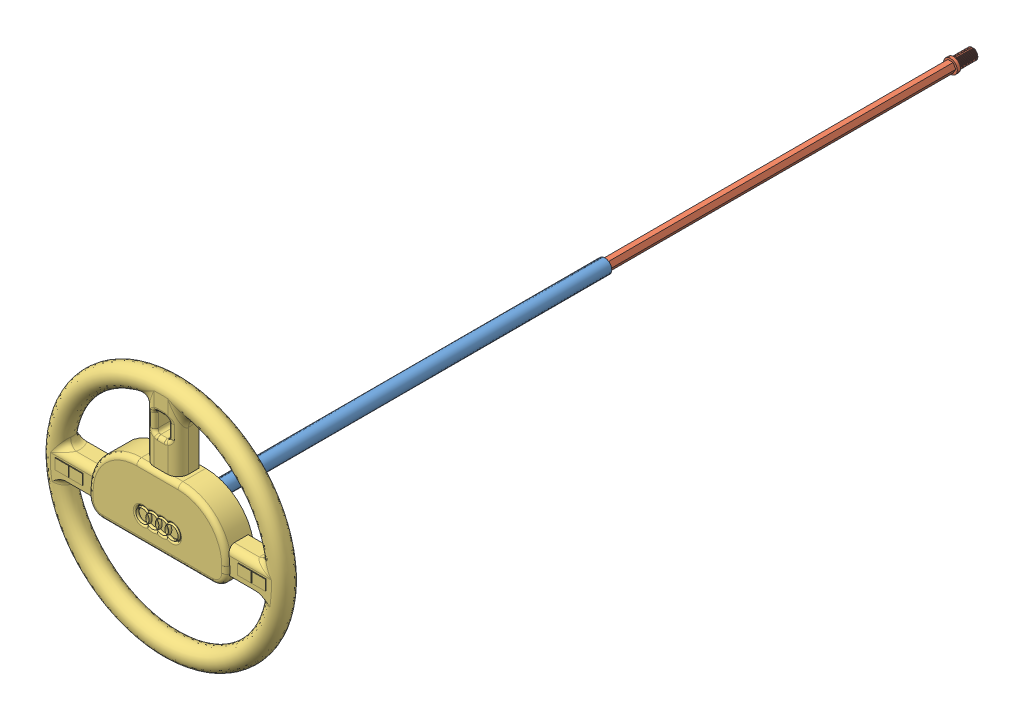
SolidWorks assembly Assem3, configuration Default. Lengths in mm.
Overall size (350 350 1180.07).
3 component instances, 3 part files, 5 mates.
Components (placement in the parent):
- TRỤC VÔ LĂNG-1: TRỤC VÔ LĂNG [Default] at (0 0 -605) size (20 20 622.5)
- TRỤC VÔ LĂNG 2-1: TRỤC VÔ LĂNG 2 [Default] at (0 0 -627.5) x (-1 0 0) z (0 0 -1) size (20 20 532)
- VÔ LĂNG-1: VÔ LĂNG [Default] at origin size (350 350 50.57)
Mates (geometry in assembly coordinates):
- Concentric1: concentric anti-aligned: cylinder of TRỤC VÔ LĂNG-1 through (0 0 -89.2536) axis (0 0 -1) radius 10; cylinder of TRỤC VÔ LĂNG 2-1 through (0 0 -1216.7536) axis (0 0 1) radius 10
- Coincident4: coincident anti-aligned: plane of TRỤC VÔ LĂNG-1 through (0 0 -711.7536) normal (0 0 -1); plane of TRỤC VÔ LĂNG 2-1 through (0 0 -711.7536) normal (0 0 1)
- Coincident5: coordinate: point of VÔ LĂNG-1
- Concentric2: concentric aligned: circle of TRỤC VÔ LĂNG-1; circle of VÔ LĂNG-1
- Coincident6: coincident anti-aligned: plane of TRỤC VÔ LĂNG-1 through (0 0 -5) normal (0 0 1); plane of VÔ LĂNG-1 through (-7.6271 1.3449 -5) normal (0 0 -1)
